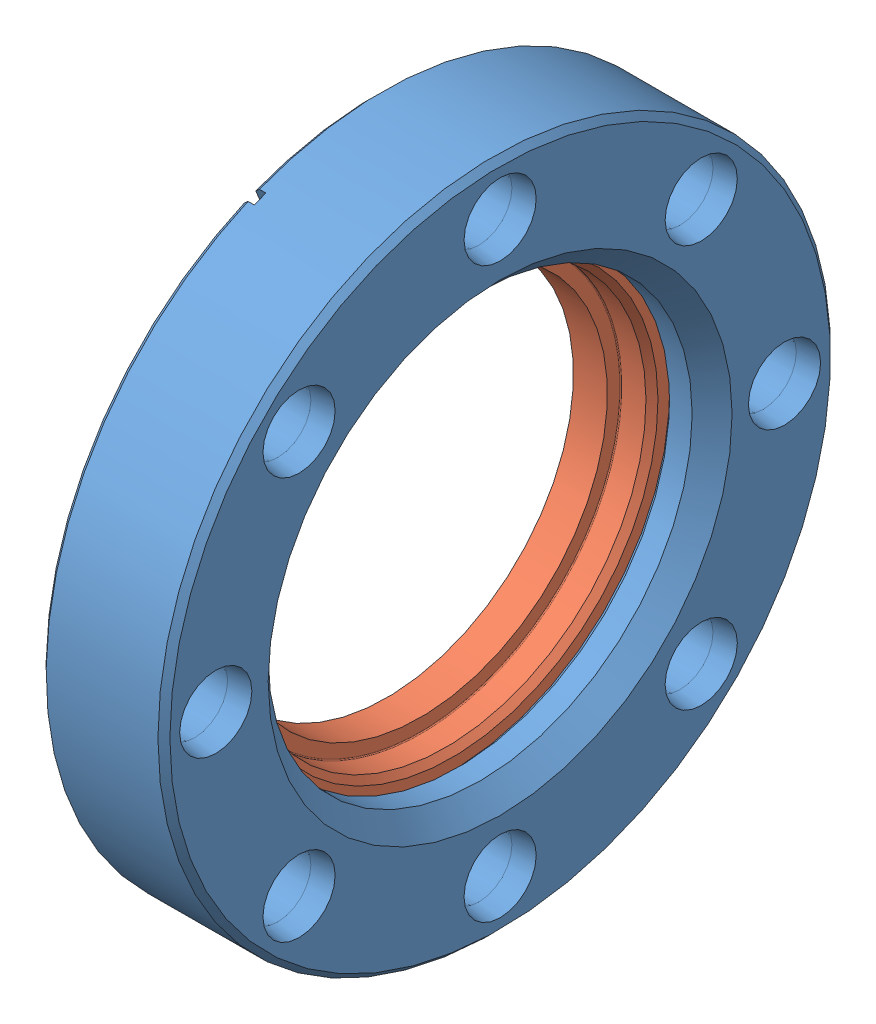
SolidWorks assembly 100017, configuration Default. Lengths in mm.
Overall size (15.76 85.6 85.6).
2 component instances, 2 part files, 2 mates.
Components (placement in the parent):
- 915003-1: 915003 [Default] at (23.7638 50.27 62.0665) size (15.76 85.6 85.6)
- 910017-1: 910017 [Default] at (24.4242 50.27 62.0665) x (1 0 0) z (0 -0.134023 0.990978) size (8.84 61.67 61.67)
Mates (geometry in assembly coordinates):
- Concentric1: concentric: cylinder of 915003-1 through (23.7638 50.27 62.0665) axis (-1 0 0) radius 42.799; cylinder of 910017-1 through (24.4242 50.27 62.0665) axis (-1 0 0) radius 30.8356
- Coincident1: coincident anti-aligned: plane of 915003-1 through (33.3142 77.2575 62.0665) normal (-1 0 0); plane of 910017-1 through (33.3142 80.8274 66.1991) normal (1 0 0)
